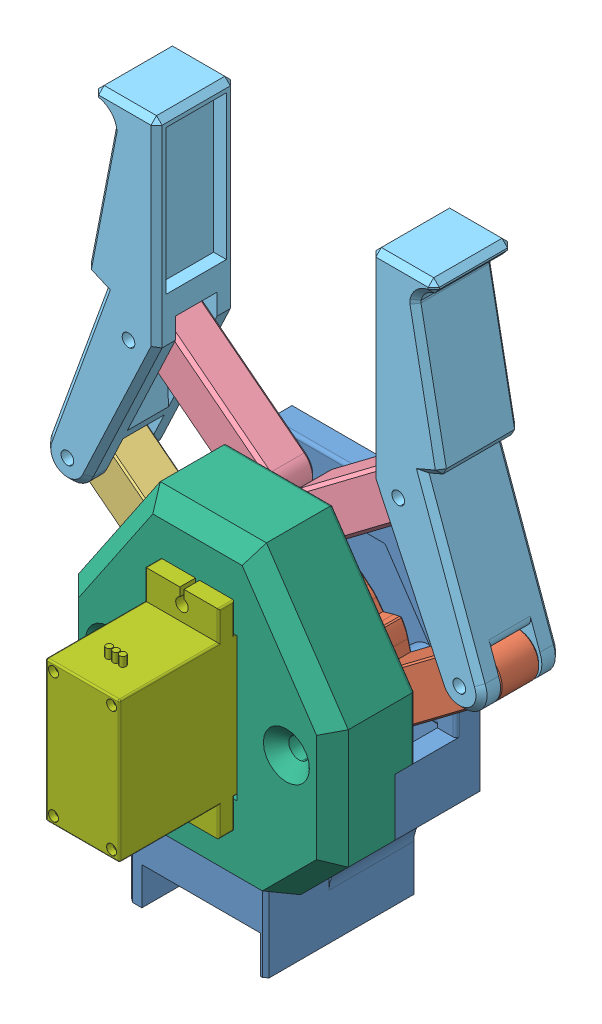
SolidWorks assembly Garra, configuration Predeterminado. Lengths in mm.
Overall size (72.7 855.85 189.81).
11 component instances, 8 part files, 22 mates.
Components (placement in the parent):
- EEZYbotARM Palm.step-1: EEZYbotARM Palm.step [Predeterminado] at (-9.8569 4.5901 44.9724) size (43.18 58.05 26.16)
- Gear Arm Right.step-1: Gear Arm Right.step [Predeterminado] at (4.3671 1.1658 51.297) x (0.601687 -0.798732 0) z (0.798732 0.601687 0) size (18.76 9.54 40.35)
- Gear Arm Left.step-1: Gear Arm Left.step [Predeterminado] at (-24.0809 1.1658 51.297) x (0.614416 0.788982 0) z (-0.788982 0.614416 0) size (18.68 6.36 40.27)
- Forward Hinge Arm.step-1: Forward Hinge Arm.step [Predeterminado] at (-5.4119 22.3701 57.647) x (-0.601687 0.798732 0) z (0 0 -1) size (7.11 28.7 6.35)
- Forward Hinge Arm.step-2: Forward Hinge Arm.step [Predeterminado] at (-14.3019 22.3701 51.297) x (0.614416 0.788982 0) z (0 0 1) size (7.11 28.7 6.35)
- Finger.step-1: Finger.step [Predeterminado] at (7.3499 21.0219 47.995) size (17.82 57.24 12.7)
- Finger.step-2: Finger.step [Predeterminado] at (-26.8532 21.2967 60.695) x (-1 0 0) z (0 0 -1) size (17.82 57.24 12.7)
- EEZYbotARM Palm Top.step-1: EEZYbotARM Palm Top.step [Predeterminado] at (-9.8569 4.5901 61.1014) size (43.18 46.02 13.18)
- sg90 micro servo-1: sg90 micro servo [Default] at (-15.7499 13.7849 62.8344) x (0 -1 0) z (1 0 0) size (855.85 189.81 11.8)
  - Part1-1: Part1 [Default] at (11.25 -26.7 0) size (855.85 189.81 11.8)
  - axis.step-1: axis.step [Default] at (5.9 3.2 5.9) x (0.296886 0 0.954913) z (0 -1 0) size (4.6 4.6 7.2)
Mates (geometry in assembly coordinates):
- Coincidente1: coincident anti-aligned: plane of EEZYbotARM Palm.step-1 through (-9.8569 6.1141 51.297) normal (0 0 1); plane of Gear Arm Right.step-1 through (15.2025 11.8103 51.297) normal (0 0 -1)
- Concéntrica1: concentric aligned: cylinder of EEZYbotARM Palm.step-1 through (4.3671 1.1658 46.1154) axis (0 0 1) radius 1.27; cylinder of Gear Arm Right.step-1 through (4.3671 1.1658 51.295) axis (0 0 1) radius 1.524
- Coincidente2: coincident anti-aligned: plane of EEZYbotARM Palm.step-1 through (-9.8569 6.1141 51.297) normal (0 0 1); plane of Gear Arm Left.step-1 through (-36.0649 10.4983 51.297) normal (0 0 -1)
- Concéntrica2: concentric aligned: cylinder of EEZYbotARM Palm.step-1 through (-24.0809 1.1658 46.1154) axis (0 0 1) radius 1.27; cylinder of Gear Arm Left.step-1 through (-24.0809 1.1658 51.295) axis (0 0 1) radius 1.524
- Coincidente3: coincident anti-aligned: plane of EEZYbotARM Palm.step-1 through (-9.8569 6.1141 51.297) normal (0 0 1); plane of Forward Hinge Arm.step-1 through (3.2104 28.8653 51.297) normal (0 0 -1)
- Concéntrica3: concentric aligned: cylinder of EEZYbotARM Palm.step-1 through (-5.4119 22.3701 46.8774) axis (0 0 1) radius 1.27; cylinder of Forward Hinge Arm.step-1 through (-5.4119 22.3701 51.297) axis (0 0 1) radius 1.524
- Coincidente4: coincident anti-aligned: plane of EEZYbotARM Palm.step-1 through (-9.8569 6.1141 51.297) normal (0 0 1); plane of Forward Hinge Arm.step-2 through (-22.8189 29.0027 51.297) normal (0 0 -1)
- Concéntrica5: concentric anti-aligned: cylinder of EEZYbotARM Palm.step-1 through (-14.3019 22.3701 46.8774) axis (0 0 1) radius 1.27; cylinder of Forward Hinge Arm.step-2 through (-14.3019 22.3701 57.647) axis (0 0 -1) radius 1.524
- Coincidente5: coincident anti-aligned: plane of Gear Arm Right.step-1 through (8.4649 4.2526 57.647) normal (0 0 1); plane of Finger.step-1 through (16.0661 23.7814 57.647) normal (0 0 -1)
- Concéntrica6: concentric aligned: cylinder of Gear Arm Right.step-1 through (21.6117 14.1562 57.647) axis (0 0 -1) radius 1.2065; cylinder of Finger.step-1 through (21.6117 14.1562 60.695) axis (0 0 -1) radius 1.016
- Concéntrica7: concentric anti-aligned: cylinder of Forward Hinge Arm.step-1 through (11.8327 35.3605 51.297) axis (0 0 1) radius 1.2065; cylinder of Finger.step-1 through (11.8327 35.3605 60.695) axis (0 0 -1) radius 1.016
- Coincidente6: coincident anti-aligned: plane of Gear Arm Left.step-1 through (-24.6891 8.7822 57.647) normal (0 0 1); plane of Finger.step-2 through (-35.5694 24.0562 57.647) normal (0 0 -1)
- Concéntrica8: concentric anti-aligned: cylinder of Gear Arm Left.step-1 through (-41.115 14.431 57.647) axis (0 0 -1) radius 1.2065; cylinder of Finger.step-2 through (-41.115 14.431 47.995) axis (0 0 1) radius 1.016
- Concéntrica9: concentric anti-aligned: cylinder of Forward Hinge Arm.step-2 through (-31.336 35.6353 57.647) axis (0 0 -1) radius 1.2065; cylinder of Finger.step-2 through (-31.336 35.6353 47.995) axis (0 0 1) radius 1.016
- Coincidente7: coincident anti-aligned: plane of EEZYbotARM Palm.step-1 through (-9.8569 4.5901 61.1014) normal (0 0 1); plane of EEZYbotARM Palm Top.step-1 through (-9.8569 4.5901 61.1014) normal (0 0 -1)
- Concéntrica10: concentric anti-aligned: cylinder of Gear Arm Left.step-1 through (-24.0809 1.1658 51.295) axis (0 0 1) radius 1.524; cylinder of EEZYbotARM Palm Top.step-1 through (-24.0809 1.1658 63.1334) axis (0 0 -1) radius 1.651
- Concéntrica11: concentric anti-aligned: cylinder of Gear Arm Right.step-1 through (4.3671 1.1658 51.295) axis (0 0 1) radius 1.524; cylinder of EEZYbotARM Palm Top.step-1 through (4.3671 1.1658 63.1334) axis (0 0 -1) radius 1.651
- Coincidente8: coincident anti-aligned: plane of EEZYbotARM Palm Top.step-1 through (-9.8569 3.4725 71.1344) normal (0 0 1); plane of sg90 micro servo-1/Part1-1 through (-3.9499 18.4849 71.1344) normal (0 0 -1)
- Coincidente9: coincident anti-aligned: plane of EEZYbotARM Palm Top.step-1 through (-9.8569 13.7849 45.7344) normal (0 -1 0); plane of sg90 micro servo-1/Part1-1 through (-3.9499 13.7849 71.1344) normal (0 1 0)
- Relación de posición de engranaje1: gear = 7 : 7 mm: cylinder of Gear Arm Right.step-1 through (4.3671 1.1658 51.295) axis (0 0 1) radius 1.524; cylinder of Gear Arm Left.step-1 through (-24.0809 1.1658 51.295) axis (0 0 1) radius 1.524
- Distancia límite2: limit distance = 34.2031 mm anti-aligned: plane of Finger.step-2 through (-26.8532 52.2364 47.995) normal (1 0 0); plane of Finger.step-1 through (7.3499 51.9616 60.695) normal (-1 0 0)
- Distancia4: distance = 0.4569 mm anti-aligned: plane of sg90 micro servo-1/Part1-1 through (-15.7499 2.5349 89.5344) normal (-1 0 0); plane of EEZYbotARM Palm Top.step-1 through (-16.2069 2.3549 45.7344) normal (1 0 0)
